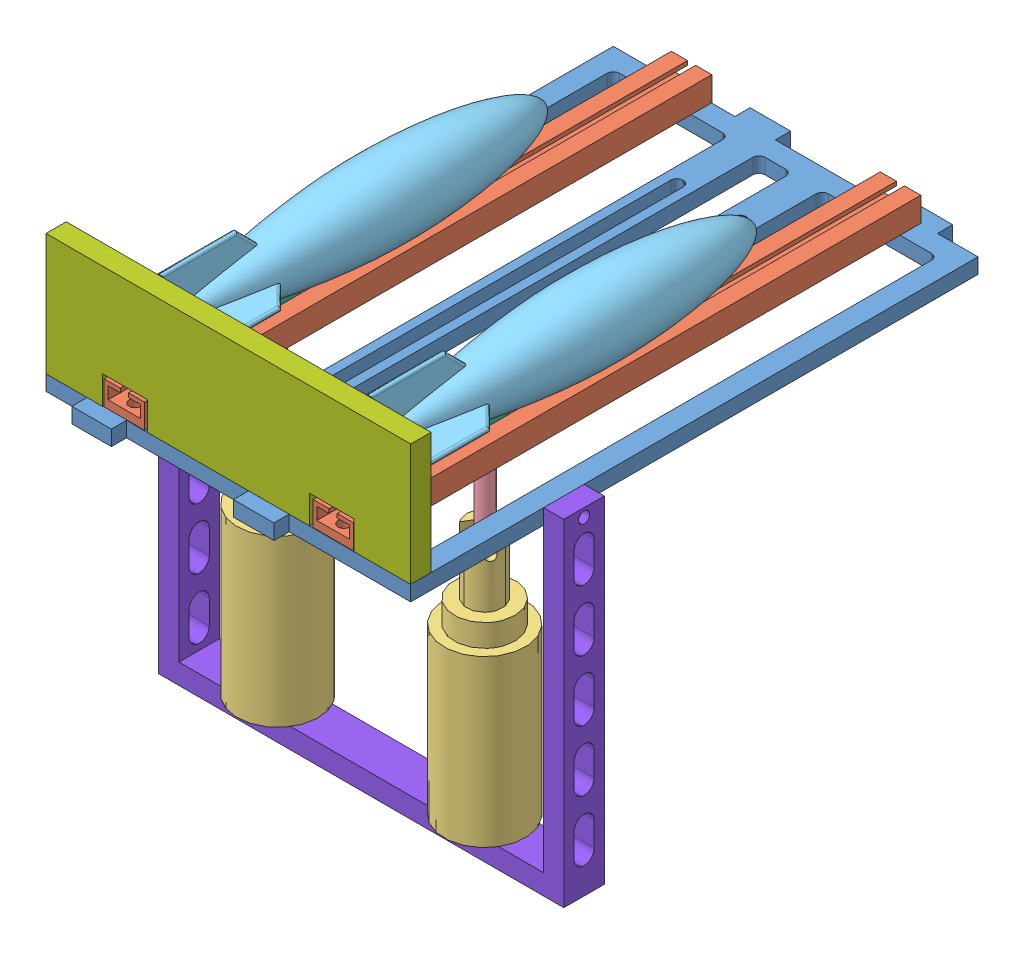
SolidWorks assembly Rail Shooter, configuration Default. Lengths in mm.
Overall size (127 143.51 187.33).
15 component instances, 8 part files, 25 mates.
Components (placement in the parent):
- Shooter Panel-1: Shooter Panel [Default] at origin size (114.3 4.76 187.33)
- Track-1: Track [Default] at (32.7343 4.7625 -89.027) x (0 0 1) z (-1 0 0) size (177.8 7.62 12.7)
- Track-2: Track [Default] at (-32.7343 4.7625 -89.027) x (0 0 1) z (-1 0 0) size (177.8 7.62 12.7)
- solenoid-1: solenoid [Default] at (32.3245 -94.1235 40.9058) x (0.860194 0 0.509966) z (0 1 0) size (25.4 25.4 78.99)
- solenoid-2: solenoid [Default] at (-32.7184 -94.1235 40.6723) x (-0.034664 0 0.999399) z (0 1 0) size (25.4 25.4 78.99)
- Trigger-1: Trigger [Default] at (32.7343 7.3025 41.148) x (0.860194 0 0.509966) z (0.509966 0 -0.860194) size (5.08 30.48 5.08)
- Trigger-2: Trigger [Default] at (-32.7343 7.3025 41.148) x (-0.034664 0 0.999399) z (0.999399 0 0.034664) size (5.08 30.48 5.08)
- Toypedo plus rail-1: Toypedo plus rail [Default] at (32.7322 24.16 -42.7371) x (0 0 -1) z (1 0 0) size (123.83 34.75 34.75)
  - Toypedo-1: Toypedo [Default] at origin size (123.83 34.75 34.75)
  - Trigger Lock-1: Trigger Lock [Default] at (-90.2483 -16.8575 0.002) size (12.7 16.51 10.16)
- Toypedo plus rail-2: Toypedo plus rail [Default] at (-32.7363 24.16 -42.7371) x (0 0 -1) z (1 0 0) size (123.83 34.75 34.75)
  - Toypedo-1: Toypedo [Default] at origin size (123.83 34.75 34.75)
  - Trigger Lock-1: Trigger Lock [Default] at (-90.2483 -16.8575 0.002) size (12.7 16.51 10.16)
- Back Plate-1: Back Plate [Default] at (0 4.7625 82.55) size (114.3 38.1 6.35)
- Solenoid Mount-1: Solenoid Mount [Default] at (60.325 4.7625 40.903) x (0 0 -1) z (1 0 0) size (12.7 105.41 127)
Mates (geometry in assembly coordinates):
- Coincident3: coincident anti-aligned: plane of Shooter Panel-1 through (-57.15 4.7625 88.9) normal (0 1 0); plane of Track-1 through (26.3843 4.7625 88.773) normal (0 -1 0)
- Coincident4: coincident anti-aligned: plane of Shooter Panel-1 through (-57.15 4.7625 88.9) normal (0 1 0); plane of Track-2 through (-39.0843 4.7625 88.773) normal (0 -1 0)
- Concentric2: concentric aligned: cylinder of Shooter Panel-1 through (-32.7343 4.7625 -85.725) axis (0 1 0) radius 1.786; cylinder of Track-2 through (-32.7343 7.3025 -85.725) axis (0 1 0) radius 1.786
- Concentric3: concentric aligned: cylinder of Shooter Panel-1 through (32.7343 4.7625 -85.725) axis (0 1 0) radius 1.786; cylinder of Track-1 through (32.7343 7.3025 -85.725) axis (0 1 0) radius 1.786
- Parallel1: parallel anti-aligned: line of Shooter Panel-1 through (-19.05 4.7625 -88.9) axis (-1 0 0); line of Track-2 through (-39.0843 4.7625 -89.027) axis (1 0 0)
- Parallel2: parallel anti-aligned: line of Shooter Panel-1 through (31.75 4.7625 -88.9) axis (-1 0 0); line of Track-1 through (26.3843 4.7625 -89.027) axis (1 0 0)
- Concentric5: concentric aligned: cylinder of solenoid-1 through (42.6471 -20.1295 47.0249) axis (-0.860194 0 -0.509966) radius 1.5; cylinder of Trigger-1 through (40.0253 -20.1295 45.4705) axis (-0.860194 0 -0.509966) radius 1.524
- Coincident11: coincident anti-aligned: plane of solenoid-1 through (37.1047 -25.1295 36.7646) normal (-0.860194 0 -0.509966); plane of Trigger-1 through (31.5983 -13.0175 46.0525) normal (0.860194 0 0.509966)
- Concentric6: concentric aligned: cylinder of solenoid-2 through (-33.1337 -20.1295 52.6651) axis (0.034664 0 -0.999399) radius 1.5; cylinder of Trigger-2 through (-33.0281 -20.1295 49.6189) axis (0.034664 0 -0.999399) radius 1.524
- Coincident12: coincident anti-aligned: plane of solenoid-2 through (-26.7913 -25.1295 42.879) normal (0.034664 0 -0.999399); plane of Trigger-2 through (-37.5823 -13.0175 42.5048) normal (-0.034664 0 0.999399)
- Parallel3: parallel anti-aligned: line of solenoid-1 through (33.2511 -15.1295 35.4209) axis (0 -1 0); line of Trigger-1 through (32.4596 -23.1775 38.6229) axis (0 1 0)
- Parallel4: parallel anti-aligned: line of solenoid-2 through (-27.4615 -15.1295 38.8534) axis (0 -1 0); line of Trigger-2 through (-30.6506 -23.1775 39.6954) axis (0 1 0)
- Coincident15: coincident anti-aligned: plane of Track-2 through (-27.6542 7.3025 88.773) normal (0 1 0); plane of Toypedo plus rail-2/Trigger Lock-1 through (-37.8143 7.3025 34.8112) normal (0 -1 0)
- Coincident16: coincident anti-aligned: plane of Track-2 through (-27.6542 11.1125 88.773) normal (-1 0 0); plane of Toypedo plus rail-2/Trigger Lock-1 through (-27.6542 11.1125 34.8112) normal (1 0 0)
- Coincident17: coincident anti-aligned: plane of Track-1 through (37.8143 11.1125 88.773) normal (-1 0 0); plane of Toypedo plus rail-1/Trigger Lock-1 through (37.8143 11.1125 34.8112) normal (1 0 0)
- Coincident18: coincident anti-aligned: plane of Track-1 through (37.8143 7.3025 88.773) normal (0 1 0); plane of Toypedo plus rail-1/Trigger Lock-1 through (27.6542 7.3025 34.8112) normal (0 -1 0)
- Concentric9: concentric aligned: cylinder of Track-2 through (-32.7343 4.7625 41.148) axis (0 1 0) radius 3.175; cylinder of Trigger-2 through (-32.7343 -23.1775 41.148) axis (0 1 0) radius 2.54
- Coincident20: coincident aligned: plane of Track-2 through (-27.6542 7.3025 88.773) normal (0 1 0); plane of Trigger-2 through (-32.7343 7.3025 41.148) normal (0 1 0)
- Concentric10: concentric aligned: cylinder of Track-1 through (32.7343 4.7625 41.148) axis (0 1 0) radius 3.175; cylinder of Trigger-1 through (32.7343 -23.1775 41.148) axis (0 1 0) radius 2.54
- Coincident21: coincident aligned: plane of Track-1 through (37.8143 7.3025 88.773) normal (0 1 0); plane of Trigger-1 through (32.7343 7.3025 41.148) normal (0 1 0)
- Coincident22: coincident aligned: plane of Toypedo plus rail-1/Toypedo-1 through (32.7322 24.16 81.0879) normal (0 0 1); plane of Toypedo plus rail-2/Toypedo-1 through (-32.7363 24.16 81.0879) normal (0 0 1)
- Coincident23: coincident aligned: plane of Shooter Panel-1 through (57.15 4.7625 88.9) normal (0 0 1); plane of Back Plate-1 through (-57.15 4.7625 88.9) normal (0 0 1)
- Coincident25: coincident anti-aligned: plane of Shooter Panel-1 through (-57.15 4.7625 88.9) normal (0 1 0); plane of Back Plate-1 through (-25.4 4.7625 88.9) normal (0 -1 0)
- Coincident28: coincident: plane of Shooter Panel-1 through (-57.15 4.7625 88.9) normal (0 1 0); plane of Solenoid Mount-1 through (44.45 4.7625 34.553) normal (0 1 0)
- Coincident32: coincident anti-aligned: plane of Shooter Panel-1 through (57.15 4.7625 -88.9) normal (1 0 0); plane of Solenoid Mount-1 through (57.15 -100.6475 47.253) normal (-1 0 0)
